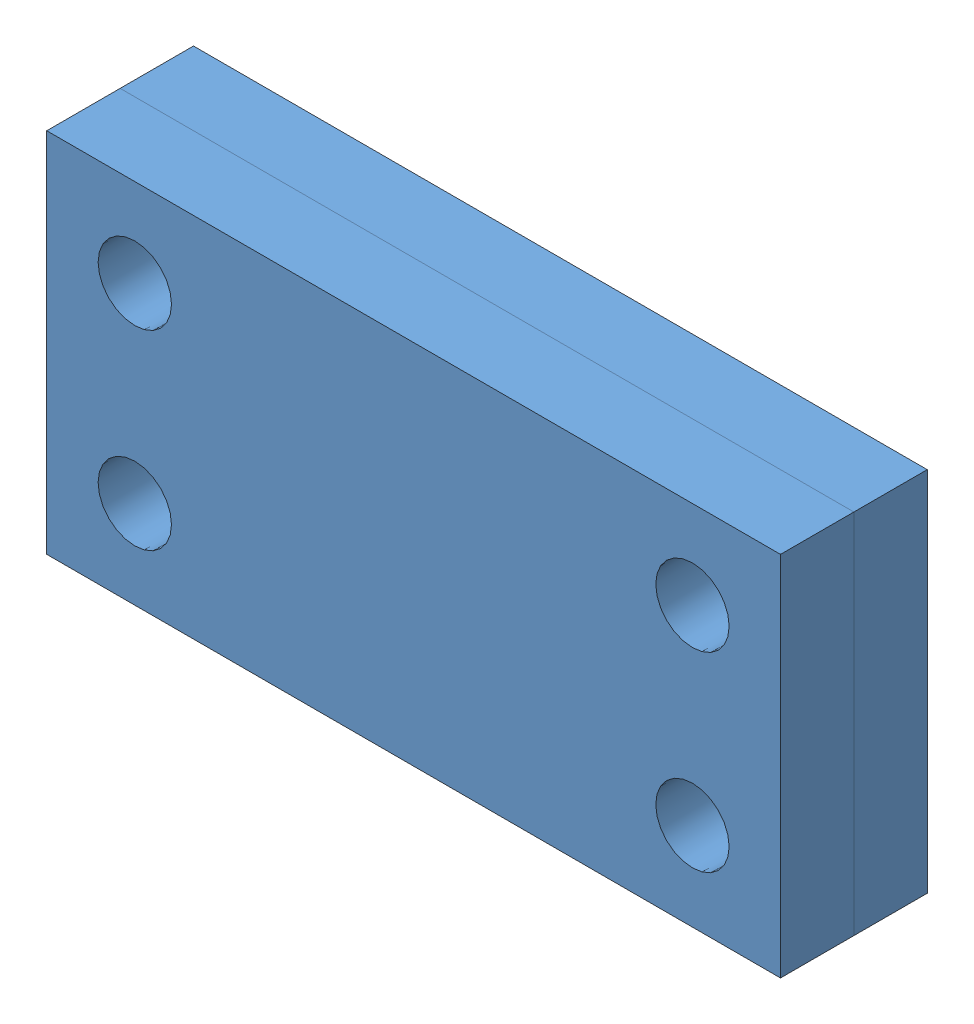
SolidWorks assembly Ensamblaje1, configuration Predeterminado. Lengths in mm.
Overall size (100 50 20).
2 component instances, 1 part files, 3 mates.
Components (placement in the parent):
- Pieza1-1: Pieza1 [Predeterminado] at (-56.5821 -19.0864 95) size (100 50 10)
- Pieza1-2: Pieza1 [Predeterminado] at (-56.5821 -19.0864 105) size (100 50 10)
Mates (geometry in assembly coordinates):
- Coincidente1: coincident: plane of assembly; plane of assembly; plane of Pieza1-1 through (-56.5821 30.9136 105) normal (0 1 0); plane of Pieza1-2 through (-56.5821 30.9136 115) normal (0 1 0)
- Coincidente2: coincident: plane of assembly; plane of assembly; plane of Pieza1-1 through (43.4179 -19.0864 105) normal (1 0 0); plane of Pieza1-2 through (43.4179 -19.0864 115) normal (1 0 0)
- Coincidente3: coincident: plane of assembly; plane of assembly; plane of Pieza1-1 through (-56.5821 -19.0864 105) normal (0 0 1); plane of Pieza1-2 through (-56.5821 -19.0864 105) normal (0 0 -1)
